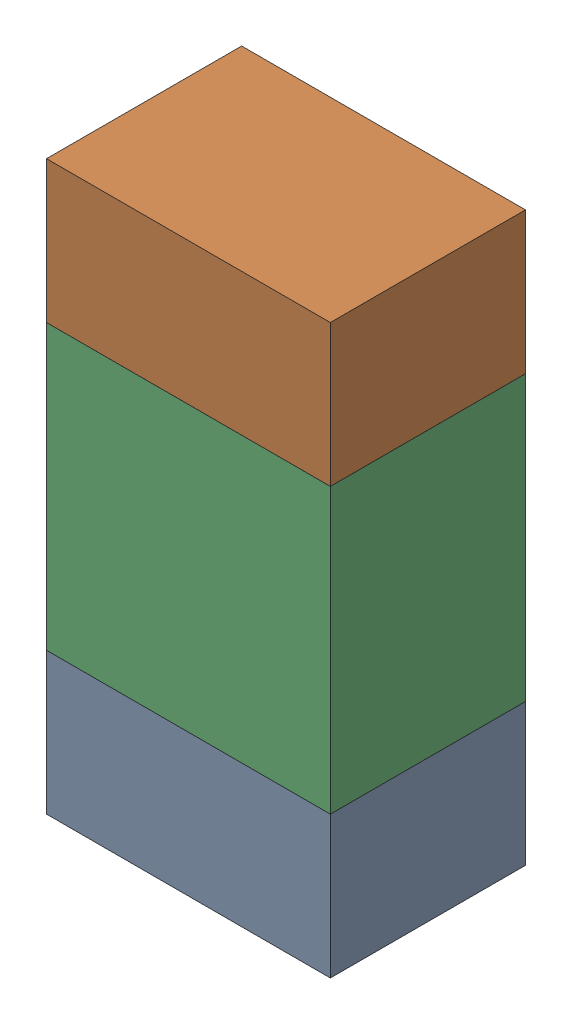
SolidWorks assembly R39, configuration ﾃﾞﾌｫﾙﾄ. Lengths in mm.
Overall size (0.8 1.6 0.55).
6 component instances, 2 part files, 0 mates.
Components (placement in the parent):
- 689261784-1: 689261784 [ﾃﾞﾌｫﾙﾄ] at (16.4999 69.1501 0) size (0.8 0.4 0.55)
  - Extruded_34-1: Extruded_34 [ﾃﾞﾌｫﾙﾄ] at origin size (0.8 0.4 0.55)
- 689261784-2: 689261784 [ﾃﾞﾌｫﾙﾄ] at (16.4999 70.3501 0) size (0.8 0.4 0.55)
  - Extruded_34-1: Extruded_34 [ﾃﾞﾌｫﾙﾄ] at origin size (0.8 0.4 0.55)
- 689261648-1: 689261648 [ﾃﾞﾌｫﾙﾄ] at (16.4999 69.75 0) size (0.8 0.8 0.55)
  - Extruded_33-1: Extruded_33 [ﾃﾞﾌｫﾙﾄ] at origin size (0.8 0.8 0.55)
